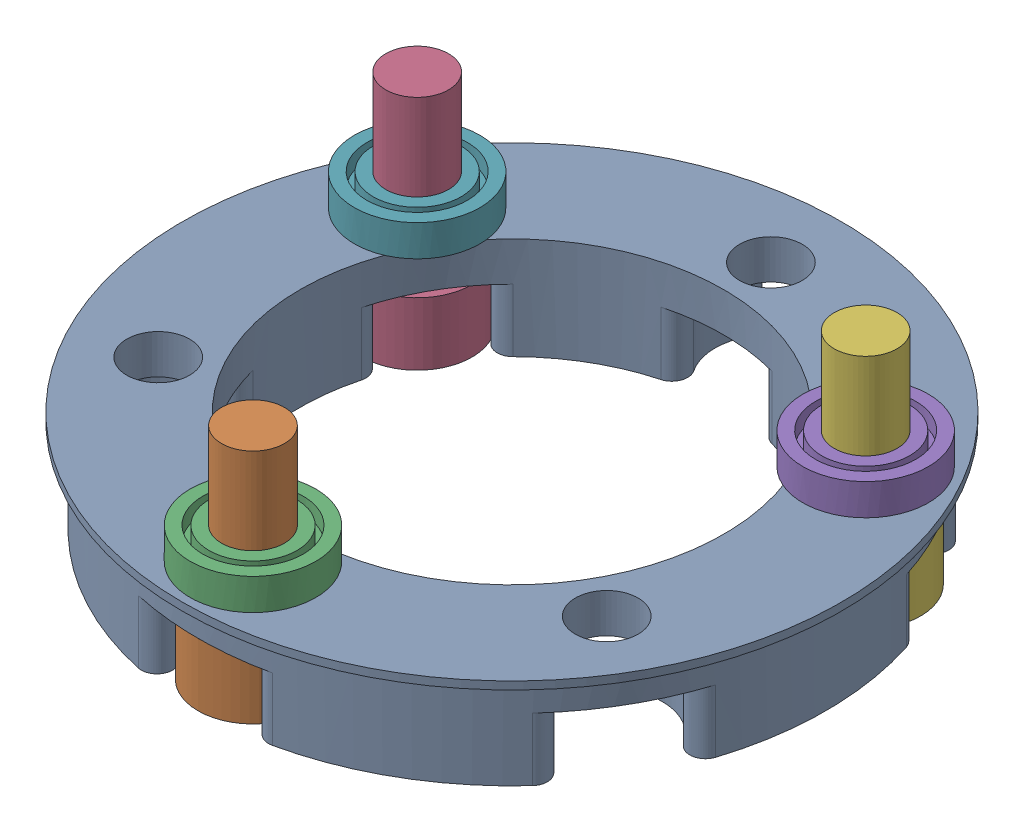
SolidWorks assembly OutputShaftAssem, configuration Default. Lengths in mm.
Overall size (42 14 42).
7 component instances, 3 part files, 12 mates.
Components (placement in the parent):
- OutputShaftBottom-1: OutputShaftBottom [Default] at (12.545 7.0896 19.1173) size (42 6.5 42)
- M4_10mm-1: M4_10mm [Default] at (12.545 7.0896 35.6173) size (7 14 7)
- 4x8x3_bearing_uxcell-1: 4x8x3_bearing_uxcell [Default] at (12.545 12.5896 35.6173) size (8 2 8)
- M4_10mm-2: M4_10mm [Default] at (-1.7444 7.0896 10.8673) size (7 14 7)
- 4x8x3_bearing_uxcell-2: 4x8x3_bearing_uxcell [Default] at (26.8344 12.5896 10.8673) size (8 2 8)
- M4_10mm-3: M4_10mm [Default] at (26.8344 7.0896 10.8673) size (7 14 7)
- 4x8x3_bearing_uxcell-3: 4x8x3_bearing_uxcell [Default] at (-1.7444 12.5896 10.8673) size (8 2 8)
Mates (geometry in assembly coordinates):
- Coincident1: coincident anti-aligned: plane of OutputShaft-1 through (12.545 11.0896 35.6173) normal (0 -1 0); plane of M4_10mm-1 through (12.545 11.0896 35.6173) normal (0 1 0)
- Concentric1: concentric anti-aligned: cylinder of OutputShaft-1 through (12.545 7.0896 35.6173) axis (0 1 0) radius 2; cylinder of M4_10mm-1 through (12.545 21.0896 35.6173) axis (0 -1 0) radius 2
- Concentric2: concentric aligned: cylinder of M4_10mm-1 through (12.545 21.0896 35.6173) axis (0 -1 0) radius 2; cylinder of 4x8x3_bearing_uxcell-1 through (12.545 15.5896 35.6173) axis (0 -1 0) radius 2
- Coincident2: coincident anti-aligned: plane of OutputShaft-1 through (12.545 13.5896 19.1173) normal (0 1 0); plane of 4x8x3_bearing_uxcell-1 through (12.545 13.5896 35.6173) normal (0 -1 0)
- Concentric3: concentric anti-aligned: cylinder of OutputShaft-1 through (26.8344 7.0896 10.8673) axis (0 1 0) radius 2; cylinder of M4_10mm-3 through (26.8344 21.0896 10.8673) axis (0 -1 0) radius 2
- Concentric4: concentric anti-aligned: cylinder of OutputShaft-1 through (-1.7444 7.0896 10.8673) axis (0 1 0) radius 2; cylinder of M4_10mm-2 through (-1.7444 21.0896 10.8673) axis (0 -1 0) radius 2
- Coincident3: coincident anti-aligned: plane of OutputShaft-1 through (26.8344 11.0896 10.8673) normal (0 -1 0); plane of M4_10mm-3 through (26.8344 11.0896 10.8673) normal (0 1 0)
- Coincident4: coincident anti-aligned: plane of OutputShaft-1 through (-1.7444 11.0896 10.8673) normal (0 -1 0); plane of M4_10mm-2 through (-1.7444 11.0896 10.8673) normal (0 1 0)
- Concentric6: concentric aligned: cylinder of 4x8x3_bearing_uxcell-2 through (26.8344 15.5896 10.8673) axis (0 -1 0) radius 2; cylinder of M4_10mm-3 through (26.8344 21.0896 10.8673) axis (0 -1 0) radius 2
- Concentric7: concentric aligned: cylinder of M4_10mm-2 through (-1.7444 21.0896 10.8673) axis (0 -1 0) radius 2; cylinder of 4x8x3_bearing_uxcell-3 through (-1.7444 15.5896 10.8673) axis (0 -1 0) radius 2
- Coincident5: coincident anti-aligned: plane of OutputShaft-1 through (12.545 13.5896 19.1173) normal (0 1 0); plane of 4x8x3_bearing_uxcell-2 through (26.8344 13.5896 10.8673) normal (0 -1 0)
- Coincident6: coincident anti-aligned: plane of OutputShaft-1 through (12.545 13.5896 19.1173) normal (0 1 0); plane of 4x8x3_bearing_uxcell-3 through (-1.7444 13.5896 10.8673) normal (0 -1 0)
